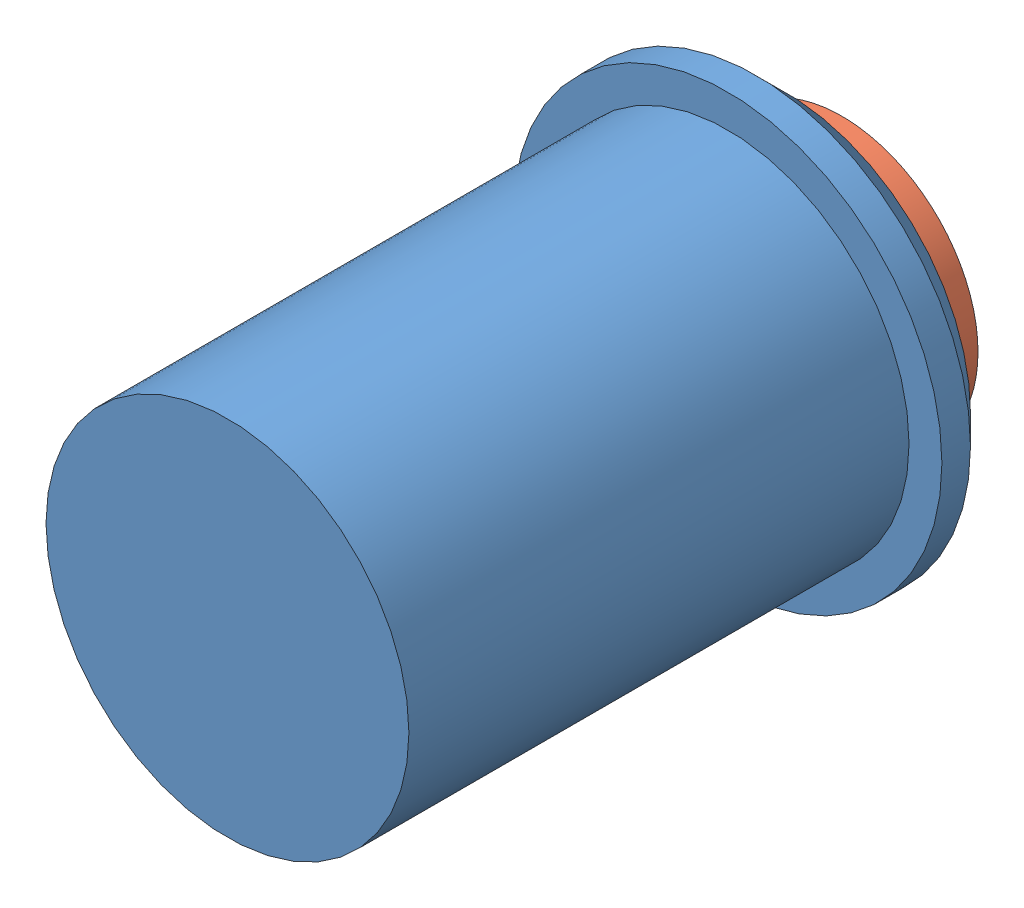
SolidWorks assembly ds-228, configuration Default. Lengths in mm.
Overall size (15 15 23.05).
2 component instances, 2 part files, 2 mates.
Components (placement in the parent):
- button case-1: button case [Default] at (-8.9217 10.0503 23.6022) size (15 15 19.5)
- button cap-1: button cap [Default] at (-8.9217 10.0503 4.1022) x (1 0 0) z (0 1 0) size (9.53 3.55 9.53)
Mates (geometry in assembly coordinates):
- Concentric1: concentric anti-aligned: cylinder of button case-1 through (-8.9217 10.0503 4.1022) axis (0 0 -1) radius 4.7625; cylinder of button cap-1 through (-8.9217 10.0503 4.1022) axis (0 0 1) radius 4.7625
- Coincident1: coincident anti-aligned: plane of button case-1 through (-2.4217 10.0503 4.1022) normal (0 0 -1); plane of button cap-1 through (-8.9217 10.0503 4.1022) normal (0 0 1)
